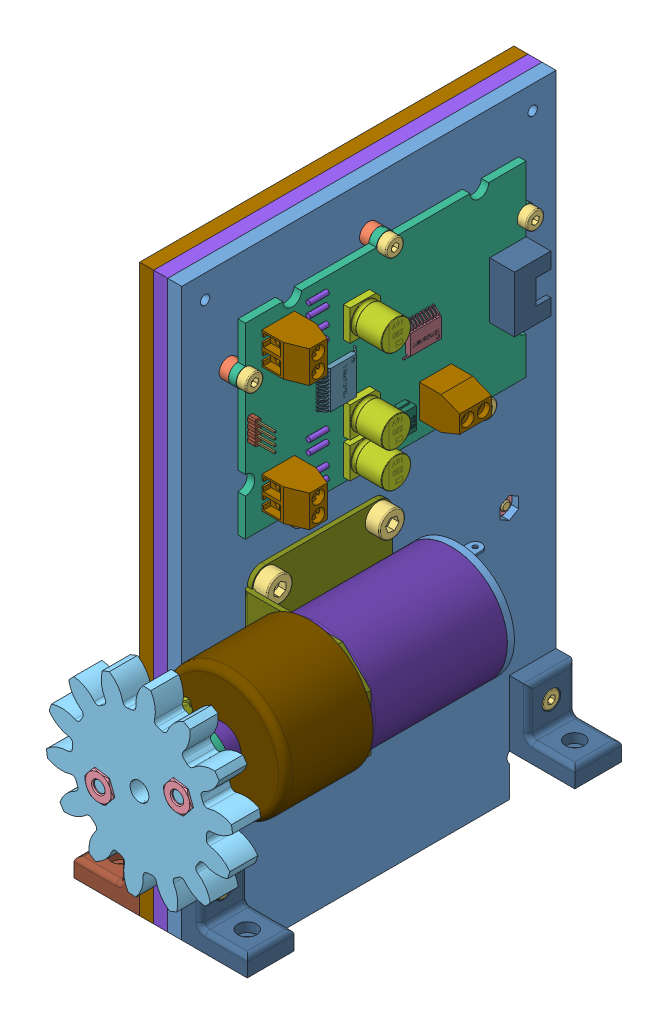
SolidWorks assembly moteur-complet, configuration Défaut. Lengths in mm.
Overall size (62.95 130 103.93).
88 component instances, 29 part files, 109 mates.
Components (placement in the parent):
- moteur-platine-1-4: moteur-platine-1 [Défaut] at (-59.9962 -68.9698 170) size (3 130 80)
- Grove button-1: Grove button [Défaut] at (-66.7015 -12.8903 110) x (0 -1 0) z (0 0 -1) size (20 11.6 23.6)
  - PCB grove 20x20-1: PCB grove 20x20 [Défaut] at (2.0795 1.2947 0) size (20 1.6 23.6)
  - 603 resistor 102-1: 603 resistor 102 [Default] at (2.0895 2.8947 -6.319) x (0 0 1) z (-1 0 0) size (2.36 0.62 1.03)
  - tactileswitch-CMS-1: tactileswitch-CMS [Default] at (-2.4169 2.8947 0.0035) x (0 0 1) z (-1 0 0) size (8.41 4.95 6.01)
  - Connecteur Grove (droit CMS)-1: Connecteur Grove (droit CMS) [Défaut] at (5.0795 2.8947 0) x (-1 0 0) z (0 1 0) size (6.5 14 10)
  - 603 resistor 102-2: 603 resistor 102 [Default] at (3.5895 2.8947 -6.319) x (0 0 1) z (-1 0 0) size (2.36 0.62 1.03)
- Grove I2C Motor driver TB6612FNG-1: Grove I2C Motor driver TB6612FNG [Défaut] at (-118.1962 28.5169 135.6463) x (0 0 1) z (1 0 0) size (64 44 12.2)
  - Plaque de base-1: Plaque de base [Défaut] at (-5.6463 -2.5133 63.2) size (64 44 1.6)
  - CS 220 16V-1: CS 220 16V [Défaut] at (0.1237 13.2167 64.8) x (1 0 0) z (0 -1 0) size (6.54 8.01 6.54)
  - CS 220 16V-2: CS 220 16V [Défaut] at (0.1237 5.6767 64.8) x (1 0 0) z (0 -1 0) size (6.54 8.01 6.54)
  - CS 220 16V-3: CS 220 16V [Défaut] at (0.1237 -12.2433 64.8) x (1 0 0) z (0 -1 0) size (6.54 8.01 6.54)
  - D1-1: D1 [Défaut] at (7.4081 5.2819 65.3) x (0 0.946795 -0.321836) z (1 0 0) size (1 1 4)
  - D1-2: D1 [Défaut] at (7.4081 7.7235 65.3) x (0 0.786026 0.618193) z (1 0 0) size (1 1 4)
  - D1-3: D1 [Défaut] at (7.4081 14.4025 65.3) x (0 0.953842 0.300308) z (1 0 0) size (1 1 4)
  - D1-4: D1 [Défaut] at (7.4081 11.9602 65.3) x (0 0.659384 0.751806) z (1 0 0) size (1 1 4)
  - D1-5: D1 [Défaut] at (7.4081 -17.5815 65.3) x (0 -0.999835 -0.018161) z (1 0 0) size (1 1 4)
  - D1-6: D1 [Défaut] at (7.4081 -14.133 65.3) x (0 0.806812 -0.590809) z (1 0 0) size (1 1 4)
  - D1-7: D1 [Défaut] at (7.4081 -11.4343 65.3) x (0 -0.166774 0.985995) z (1 0 0) size (1 1 4)
  - D1-8: D1 [Défaut] at (7.4081 -20.0356 65.3) x (0 0.962631 -0.270816) z (1 0 0) size (1 1 4)
  - bornier double-1: bornier double [Défaut] at (20.8537 7.1995 64.8) x (0 1 0) z (1 0 0) size (6.8 12.2 7)
  - bornier double-2: bornier double [Défaut] at (-12.8463 13.9867 64.8) x (-1 0 0) z (0 1 0) size (6.8 12.2 7)
  - bornier double-3: bornier double [Défaut] at (20.8537 -19.5133 64.8) x (0 1 0) z (1 0 0) size (6.8 12.2 7)
  - Grove Connecteur-1: Grove Connecteur [Défaut] at (-37.0963 -2.5133 64.05) x (1 0 0) z (0 -1 0) size (7.8 5.3 12)
  - Bloc 4 pins male-1: Bloc 4 pins male [Défaut] at (23.2493 -0.7812 63.276) x (0 -1 0) z (0 0 1) size (5.08 1.27 7.62)
    - Pin_cmi2c_Base-1: Pin_cmi2c_Base [Défaut] at (-0.1729 -0.0306 1.524) size (1.27 1.27 1.52)
    - Pin_cmi2c-1: Pin_cmi2c [Défaut] at (-0.1729 0.1472 -0.762) x (1 0 0) z (0 -1 0) size (0.36 7.62 0.36)
    - Pin_cmi2c-2: Pin_cmi2c [Défaut] at (1.0971 0.1472 -0.762) x (1 0 0) z (0 -1 0) size (0.36 7.62 0.36)
    - Pin_cmi2c-3: Pin_cmi2c [Défaut] at (2.3671 0.1472 -0.762) x (1 0 0) z (0 -1 0) size (0.36 7.62 0.36)
    - Pin_cmi2c-4: Pin_cmi2c [Défaut] at (3.6371 0.1472 -0.762) x (1 0 0) z (0 -1 0) size (0.36 7.62 0.36)
    - Pin_cmi2c_Base-2: Pin_cmi2c_Base [Défaut] at (1.0971 -0.0306 1.524) size (1.27 1.27 1.52)
    - Pin_cmi2c_Base-3: Pin_cmi2c_Base [Défaut] at (2.3671 -0.0306 1.524) size (1.27 1.27 1.52)
    - Pin_cmi2c_Base-4: Pin_cmi2c_Base [Défaut] at (3.6371 -0.0306 1.524) size (1.27 1.27 1.52)
  - Microcontroller 32F030F4P6-1: Microcontroller 32F030F4P6 [Défaut] at (-12.4961 -2.5519 65.5199) size (6.61 6.93 1.72)
  - Microcontroller TB6612FNG-1: Microcontroller TB6612FNG [Défaut] at (5.1421 -2.7086 65.5199) x (0 1 0) z (0 0 1) size (8 8.26 1.72)
  - PK13-1: PK13 [Défaut] at (-8.5328 11.2953 64.8) x (0 -1 0) z (-1 0 0) size (5.33 2 3.32)
- moteur MFA-1: moteur MFA [Défaut] at (-44.4916 -13.5198 141.6132) x (0 0 -1) z (0 -1 0) size (69.13 27.9 30)
  - moteur-support-1: moteur-support [Défaut] at (-14.3868 -12.5047 0) size (31 26.4 30)
  - moteur-corps-1: moteur-corps [Défaut] at (14.8132 1.8953 0) x (0 0 1) z (-1 0 0) size (24 24 62.63)
  - moteur-capuchon-1: moteur-capuchon [Défaut] at (-15.3868 1.8953 0) x (0 0 1) z (-1 0 0) size (27 27 18.7)
  - moteur-arriere-1: moteur-arriere [Défaut] at (16.3132 1.8953 0) x (0 0 1) z (-1 0 0) size (24 24 6.5)
- entretoise-grove-1: entretoise-grove [Défaut] at (-54.9962 51.0302 130) x (0 0.271539 0.962428) z (-1 0 0) size (4 4 2)
- entretoise-grove-2: entretoise-grove [Défaut] at (-54.9962 41.0302 100) x (0 0.358036 0.933708) z (-1 0 0) size (4 4 2)
- entretoise-grove-3: entretoise-grove [Défaut] at (-54.9962 41.0302 160) x (0 -0.42455 0.905404) z (-1 0 0) size (4 4 2)
- entretoise-grove-4: entretoise-grove [Défaut] at (-54.9962 11.0302 150) x (0 0 1) z (-1 0 0) size (4 4 2)
- entretoise-grove-5: entretoise-grove [Défaut] at (-54.9962 11.0302 110) x (0 0.014886 0.999889) z (-1 0 0) size (4 4 2)
- entretoise-grove-6: entretoise-grove [Défaut] at (-67.9962 -14.9698 120) x (0 0.014606 -0.999893) z (1 0 0) size (4 4 2)
- entretoise-grove-7: entretoise-grove [Défaut] at (-67.9962 -14.9698 100) x (0 0.432952 0.901417) z (1 0 0) size (4 4 2)
- vis-chc-1: vis-chc [Vis CHC M2x12] at (-69.5962 -14.9698 100) x (0 0.697993 -0.716105) z (0 0.716105 0.697993) size (3.8 14 3.8)
- vis-chc-2: vis-chc [Vis CHC M2x12] at (-69.5962 -14.9698 120) x (0 0.185382 -0.982666) z (0 0.982666 0.185382) size (3.8 14 3.8)
- vis-chc-3: vis-chc [Vis CHC M2x12] at (-53.3962 41.0302 100) x (0 0.381849 -0.924225) z (0 -0.924225 -0.381849) size (3.8 14 3.8)
- vis-chc-4: vis-chc [Vis CHC M2x12] at (-53.3962 51.0302 130) x (0 0.381849 -0.924225) z (0 -0.924225 -0.381849) size (3.8 14 3.8)
- vis-chc-5: vis-chc [Vis CHC M2x12] at (-53.3962 41.0302 160) x (0 0.381849 -0.924225) z (0 -0.924225 -0.381849) size (3.8 14 3.8)
- vis-chc-6: vis-chc [Vis CHC M2x12] at (-53.3962 11.0302 150) x (0 0.381849 -0.924225) z (0 -0.924225 -0.381849) size (3.8 14 3.8)
- vis-chc-7: vis-chc [Vis CHC M2x12] at (-53.3962 11.0302 110) x (0 0.381849 -0.924225) z (0 -0.924225 -0.381849) size (3.8 14 3.8)
- ecrou-h-2: ecrou-h [6007 HU M2] at (-59.9962 -14.9698 120) x (0 0.866025 0.5) z (0 -0.5 0.866025) size (4 1.6 4.62)
- ecrou-h-3: ecrou-h [6007 HU M2] at (-59.9962 -14.9698 100) x (0 0 1) z (0 -1 0) size (4 1.6 4.62)
- ecrou-h-4: ecrou-h [6007 HU M2] at (-64.5962 11.0302 110) x (0 0.866025 0.5) z (0 -0.5 0.866025) size (4 1.6 4.62)
- ecrou-h-5: ecrou-h [6007 HU M2] at (-64.5962 11.0302 150) x (0 0.866025 0.5) z (0 -0.5 0.866025) size (4 1.6 4.62)
- ecrou-h-6: ecrou-h [6007 HU M2] at (-64.5962 41.0302 160) x (0 0.866025 0.5) z (0 -0.5 0.866025) size (4 1.6 4.62)
- ecrou-h-7: ecrou-h [6007 HU M2] at (-64.5962 51.0302 130) x (0 0.866025 0.5) z (0 -0.5 0.866025) size (4 1.6 4.62)
- ecrou-h-8: ecrou-h [6007 HU M2] at (-64.5962 41.0302 100) x (0 0.866025 0.5) z (0 -0.5 0.866025) size (4 1.6 4.62)
- vis-chc-8: vis-chc [Vis CHC M3x10] at (-55.9962 -1.5198 129) x (0 0.773717 -0.633531) z (0 -0.633531 -0.773717) size (5.5 13 5.5)
- vis-chc-9: vis-chc [Vis CHC M3x10] at (-55.9962 -1.5198 153) x (0 0.483049 -0.875594) z (0 -0.875594 -0.483049) size (5.5 13 5.5)
- vis-chc-10: vis-chc [Vis CHC M3x10] at (-55.9962 -25.5198 153) x (0 0.381849 -0.924225) z (0 -0.924225 -0.381849) size (5.5 13 5.5)
- vis-chc-11: vis-chc [Vis CHC M3x10] at (-55.9962 -25.5198 129) x (0 0.381849 -0.924225) z (0 -0.924225 -0.381849) size (5.5 13 5.5)
- ecrou-h-9: ecrou-h [6012 HU M3] at (-65.3962 -1.5198 153) x (0 0.866025 0.5) z (0 -0.5 0.866025) size (5.5 2.4 6.35)
- ecrou-h-10: ecrou-h [6012 HU M3] at (-65.3962 -25.5198 153) x (0 0.866025 0.5) z (0 -0.5 0.866025) size (5.5 2.4 6.35)
- ecrou-h-11: ecrou-h [6012 HU M3] at (-65.3962 -25.5198 129) x (0 0.866025 -0.5) z (0 0.5 0.866025) size (5.5 2.4 6.35)
- ecrou-h-12: ecrou-h [6012 HU M3] at (-65.3962 -1.5198 129) x (0 0.866025 -0.5) z (0 0.5 0.866025) size (5.5 2.4 6.35)
- vis-chc-14: vis-chc [Vis CHC M2x16] at (-54.9962 -50.9698 95) x (0 -0.431797 -0.901971) z (0 -0.901971 0.431797) size (3.8 18 3.8)
- vis-chc-15: vis-chc [Vis CHC M2x16] at (-54.9962 -50.9698 165) x (0 0.381849 -0.924225) z (0 -0.924225 -0.381849) size (3.8 18 3.8)
- ecrou-h-15: ecrou-h [6007 HU M2] at (-69.5962 -50.9698 165) x (0 1 0) z (0 0 1) size (4 1.6 4.62)
- ecrou-h-16: ecrou-h [6007 HU M2] at (-69.5962 -50.9698 95) x (0 0.5 0.866025) z (0 -0.866025 0.5) size (4 1.6 4.62)
- engrenage-complet-1: engrenage-complet [Défaut] at (-42.1676 -13.7474 193.43) x (0.932852 0.36026 0) z (0 0 -1) size (39.32 40 14.86)
  - engrenage-1: engrenage [Défaut] at (1.0609 0.1936 0) size (39.32 40 6)
  - engrenage-bague_arret-1: engrenage-bague_arret [Défaut] at (-0.3178 -0.3667 13.5) x (-1 0 0) z (0 0 -1) size (24 24 8)
  - vis-tc-m3x6-1: vis-tc-m3x6 [Défaut] at (-0.3178 -8.4167 10.5) x (-0.611546 0 0.791209) z (0.791209 0 0.611546) size (5.5 7.83 5.5)
  - vis-chc-1: vis-chc [Vis CHC M3x8] at (-9.3178 -0.3667 7.5) x (0.40091 -0.916118 0) z (-0.916118 -0.40091 0) size (5.5 11 5.5)
  - vis-chc-2: vis-chc [Vis CHC M3x8] at (8.6822 -0.3667 7.5) x (0.998484 0.055044 0) z (0.055044 -0.998484 0) size (5.5 11 5.5)
  - ecrou-h-1: ecrou-h [6012 HU M3] at (8.6822 -0.3667 -0.4) x (1 0 0) z (0 1 0) size (5.5 2.4 6.35)
  - ecrou-h-2: ecrou-h [6012 HU M3] at (-9.3178 -0.3667 -0.4) x (1 0 0) z (0 1 0) size (5.5 2.4 6.35)
- moteur-platine-2-5: moteur-platine-2 [Défaut] at (-62.9962 -68.9698 170) size (3 130 80)
- moteur-platine-3-3: moteur-platine-3 [Défaut] at (-65.9962 -68.9698 170) size (3 130 80)
- equerre-3: equerre [Défaut] at (-56.9962 -59.9698 165) x (0 0 -1) z (1 0 0) size (10 14 14)
- equerre-2: equerre [Défaut] at (-56.9962 -59.9698 95) x (0 0 -1) z (1 0 0) size (10 14 14)
- equerre-ecrou-1: equerre-ecrou [Défaut] at (-65.9962 -59.9698 95) x (0 0 1) z (-1 0 0) size (10 14 14)
- equerre-ecrou-2: equerre-ecrou [Défaut] at (-65.9962 -59.9698 165) x (0 0 1) z (-1 0 0) size (10 14 14)
Mates (geometry in assembly coordinates):
- Coïncidente1: coincident anti-aligned: plane of moteur-platine-1-4 through (-56.9962 -61.1012 161.1314) normal (1 0 0); plane of moteur MFA-1/moteur-support-1 through (-56.9962 -25.5198 153) normal (-1 0 0)
- Coaxiale1: concentric anti-aligned: cylinder of moteur-platine-1-4 through (-59.9962 -1.5198 129) axis (1 0 0) radius 1.5; cylinder of moteur MFA-1/moteur-support-1 through (-30.5962 -1.5198 129) axis (-1 0 0) radius 1.65
- Coaxiale2: concentric anti-aligned: cylinder of moteur-platine-1-4 through (-59.9962 -25.5198 129) axis (1 0 0) radius 1.5; cylinder of moteur MFA-1/moteur-support-1 through (-30.5962 -25.5198 129) axis (-1 0 0) radius 1.65
- Parallèle1: parallel aligned: plane of moteur-platine-1-4 through (-56.9962 61.0302 90) normal (0 0 -1); plane of Grove I2C Motor driver TB6612FNG-1/Plaque de base-1 through (-53.3962 11.0302 100) normal (0 0 -1)
- Parallèle2: parallel aligned: plane of moteur-platine-1-4 through (-56.9962 61.0302 170) normal (0 1 0); plane of Grove I2C Motor driver TB6612FNG-1/Plaque de base-1 through (-53.3962 51.0302 132) normal (0 1 0)
- Coaxiale3: concentric anti-aligned: cylinder of Grove I2C Motor driver TB6612FNG-1/Plaque de base-1 through (-53.3962 11.0302 110) axis (-1 0 0) radius 1; cylinder of entretoise-grove-5 through (-56.9962 11.0302 110) axis (1 0 0) radius 1
- Coïncidente4: coincident anti-aligned: plane of Grove I2C Motor driver TB6612FNG-1/Plaque de base-1 through (-54.9962 21.0302 100) normal (-1 0 0); plane of entretoise-grove-5 through (-54.9962 11.0302 110) normal (1 0 0)
- Coaxiale4: concentric anti-aligned: cylinder of Grove I2C Motor driver TB6612FNG-1/Plaque de base-1 through (-53.3962 11.0302 150) axis (-1 0 0) radius 1; cylinder of entretoise-grove-4 through (-56.9962 11.0302 150) axis (1 0 0) radius 1
- Coïncidente5: coincident anti-aligned: plane of Grove I2C Motor driver TB6612FNG-1/Plaque de base-1 through (-54.9962 21.0302 100) normal (-1 0 0); plane of entretoise-grove-4 through (-54.9962 11.0302 150) normal (1 0 0)
- Coaxiale5: concentric anti-aligned: cylinder of Grove I2C Motor driver TB6612FNG-1/Plaque de base-1 through (-53.3962 41.0302 100) axis (-1 0 0) radius 1; cylinder of entretoise-grove-2 through (-56.9962 41.0302 100) axis (1 0 0) radius 1
- Coïncidente6: coincident anti-aligned: plane of Grove I2C Motor driver TB6612FNG-1/Plaque de base-1 through (-54.9962 21.0302 100) normal (-1 0 0); plane of entretoise-grove-2 through (-54.9962 41.0302 100) normal (1 0 0)
- Coaxiale6: concentric anti-aligned: cylinder of Grove I2C Motor driver TB6612FNG-1/Plaque de base-1 through (-53.3962 41.0302 160) axis (-1 0 0) radius 1; cylinder of entretoise-grove-3 through (-56.9962 41.0302 160) axis (1 0 0) radius 1
- Coïncidente7: coincident anti-aligned: plane of Grove I2C Motor driver TB6612FNG-1/Plaque de base-1 through (-54.9962 21.0302 100) normal (-1 0 0); plane of entretoise-grove-3 through (-54.9962 41.0302 160) normal (1 0 0)
- Coaxiale7: concentric anti-aligned: cylinder of Grove I2C Motor driver TB6612FNG-1/Plaque de base-1 through (-53.3962 51.0302 130) axis (-1 0 0) radius 1; cylinder of entretoise-grove-1 through (-56.9962 51.0302 130) axis (1 0 0) radius 1
- Coïncidente8: coincident anti-aligned: plane of Grove I2C Motor driver TB6612FNG-1/Plaque de base-1 through (-54.9962 21.0302 100) normal (-1 0 0); plane of entretoise-grove-1 through (-54.9962 51.0302 130) normal (1 0 0)
- Coïncidente9: coincident anti-aligned: plane of moteur-platine-1-4 through (-56.9962 -61.1012 161.1314) normal (1 0 0); plane of entretoise-grove-3 through (-56.9962 41.0302 160) normal (-1 0 0)
- Coaxiale8: concentric aligned: cylinder of moteur-platine-1-4 through (-59.9962 11.0302 150) axis (1 0 0) radius 1; cylinder of entretoise-grove-4 through (-56.9962 11.0302 150) axis (1 0 0) radius 1
- Coaxiale9: concentric anti-aligned: cylinder of Grove button-1/PCB grove 20x20-1 through (-69.5962 -14.9698 120) axis (1 0 0) radius 1.1; cylinder of entretoise-grove-6 through (-65.9962 -14.9698 120) axis (-1 0 0) radius 1
- Coaxiale10: concentric anti-aligned: cylinder of Grove button-1/PCB grove 20x20-1 through (-69.5962 -14.9698 100) axis (1 0 0) radius 1.1; cylinder of entretoise-grove-7 through (-65.9962 -14.9698 100) axis (-1 0 0) radius 1
- Coïncidente11: coincident anti-aligned: plane of Grove button-1/PCB grove 20x20-1 through (-67.9962 -14.9698 110) normal (1 0 0); plane of entretoise-grove-7 through (-67.9962 -14.9698 100) normal (-1 0 0)
- Coaxiale13: concentric anti-aligned: cylinder of moteur MFA-1/moteur-corps-1 through (-42.5962 -13.5198 189.43) axis (0 0 -1) radius 2; cylinder of engrenage-complet-1/engrenage-bague_arret-1 through (-42.5962 -13.5198 179.93) axis (0 0 1) radius 2.05
- Distance1: distance = 0.5 mm anti-aligned: plane of engrenage-complet-1/engrenage-bague_arret-1 through (-42.5962 -13.5198 179.93) normal (0 0 -1); plane of moteur MFA-1/moteur-corps-1 through (-42.5962 -13.5198 179.43) normal (0 0 1)
- Coïncidente12: coincident anti-aligned: plane of moteur-platine-1-4 through (-59.9962 -61.1012 161.1314) normal (-1 0 0); plane of moteur-platine-2-5 through (-59.9962 -61.1012 161.1314) normal (1 0 0)
- Coïncidente13: coincident aligned: plane of moteur-platine-1-4 through (-56.9962 61.0302 170) normal (0 1 0); plane of moteur-platine-2-5 through (-59.9962 61.0302 170) normal (0 1 0)
- Coïncidente14: coincident aligned: plane of moteur-platine-1-4 through (-56.9962 61.0302 90) normal (0 0 -1); plane of moteur-platine-2-5 through (-59.9962 61.0302 90) normal (0 0 -1)
- Coïncidente15: coincident anti-aligned: plane of moteur-platine-2-5 through (-62.9962 -61.1012 161.1314) normal (-1 0 0); plane of moteur-platine-3-3 through (-62.9962 -61.1012 161.1314) normal (1 0 0)
- Coïncidente16: coincident aligned: plane of moteur-platine-2-5 through (-59.9962 61.0302 170) normal (0 1 0); plane of moteur-platine-3-3 through (-62.9962 61.0302 170) normal (0 1 0)
- Coïncidente17: coincident aligned: plane of moteur-platine-1-4 through (-56.9962 61.0302 90) normal (0 0 -1); plane of moteur-platine-3-3 through (-62.9962 61.0302 90) normal (0 0 -1)
- Coïncidente18: coincident anti-aligned: plane of entretoise-grove-7 through (-65.9962 -14.9698 100) normal (1 0 0); plane of moteur-platine-3-3 through (-65.9962 -61.1012 161.1314) normal (-1 0 0)
- Coïncidente19: coincident anti-aligned: plane of entretoise-grove-6 through (-65.9962 -14.9698 120) normal (1 0 0); plane of moteur-platine-3-3 through (-65.9962 -61.1012 161.1314) normal (-1 0 0)
- Coïncidente21: coincident anti-aligned: plane of Grove button-1/PCB grove 20x20-1 through (-69.5962 -14.9698 110) normal (-1 0 0); plane of vis-chc-2 through (-69.5962 -14.9698 120) normal (1 0 0)
- Coaxiale15: concentric aligned: cylinder of vis-chc-2 through (-57.5962 -14.9698 120) axis (-1 0 0) radius 1; cylinder of ecrou-h-2 through (-58.3962 -14.9698 120) axis (-1 0 0) radius 0.7835
- Parallèle4: parallel aligned: plane of moteur-platine-1-4 through (-56.9962 61.0302 90) normal (0 0 -1); plane of ecrou-h-2 through (-58.3962 -13.8151 118) normal (0 0 -1)
- Coïncidente25: coincident anti-aligned: plane of Grove button-1/PCB grove 20x20-1 through (-69.5962 -14.9698 110) normal (-1 0 0); plane of vis-chc-1 through (-69.5962 -14.9698 100) normal (1 0 0)
- Coaxiale17: concentric aligned: cylinder of vis-chc-1 through (-57.5962 -14.9698 100) axis (-1 0 0) radius 1; cylinder of ecrou-h-3 through (-58.3962 -14.9698 100) axis (-1 0 0) radius 0.7835
- Parallèle5: parallel aligned: plane of moteur-platine-1-4 through (-56.9962 61.0302 90) normal (0 0 -1); plane of ecrou-h-3 through (-58.3962 -13.8151 98) normal (0 0 -1)
- Coaxiale18: concentric anti-aligned: cylinder of Grove I2C Motor driver TB6612FNG-1/Plaque de base-1 through (-53.3962 11.0302 110) axis (-1 0 0) radius 1; cylinder of vis-chc-7 through (-65.3962 11.0302 110) axis (1 0 0) radius 1
- Coaxiale19: concentric anti-aligned: cylinder of Grove I2C Motor driver TB6612FNG-1/Plaque de base-1 through (-53.3962 11.0302 150) axis (-1 0 0) radius 1; cylinder of vis-chc-6 through (-65.3962 11.0302 150) axis (1 0 0) radius 1
- Coaxiale20: concentric anti-aligned: cylinder of Grove I2C Motor driver TB6612FNG-1/Plaque de base-1 through (-53.3962 41.0302 160) axis (-1 0 0) radius 1; cylinder of vis-chc-5 through (-65.3962 41.0302 160) axis (1 0 0) radius 1
- Coaxiale21: concentric anti-aligned: cylinder of Grove I2C Motor driver TB6612FNG-1/Plaque de base-1 through (-53.3962 51.0302 130) axis (-1 0 0) radius 1; cylinder of vis-chc-4 through (-65.3962 51.0302 130) axis (1 0 0) radius 1
- Coaxiale22: concentric anti-aligned: cylinder of Grove I2C Motor driver TB6612FNG-1/Plaque de base-1 through (-53.3962 41.0302 100) axis (-1 0 0) radius 1; cylinder of vis-chc-3 through (-65.3962 41.0302 100) axis (1 0 0) radius 1
- Coïncidente28: coincident anti-aligned: plane of Grove I2C Motor driver TB6612FNG-1/Plaque de base-1 through (-53.3962 21.0302 100) normal (1 0 0); plane of vis-chc-3 through (-53.3962 41.0302 100) normal (-1 0 0)
- Coïncidente29: coincident anti-aligned: plane of Grove I2C Motor driver TB6612FNG-1/Plaque de base-1 through (-53.3962 21.0302 100) normal (1 0 0); plane of vis-chc-4 through (-53.3962 51.0302 130) normal (-1 0 0)
- Coïncidente30: coincident anti-aligned: plane of Grove I2C Motor driver TB6612FNG-1/Plaque de base-1 through (-53.3962 21.0302 100) normal (1 0 0); plane of vis-chc-5 through (-53.3962 41.0302 160) normal (-1 0 0)
- Coïncidente31: coincident anti-aligned: plane of Grove I2C Motor driver TB6612FNG-1/Plaque de base-1 through (-53.3962 21.0302 100) normal (1 0 0); plane of vis-chc-6 through (-53.3962 11.0302 150) normal (-1 0 0)
- Coïncidente32: coincident anti-aligned: plane of Grove I2C Motor driver TB6612FNG-1/Plaque de base-1 through (-53.3962 21.0302 100) normal (1 0 0); plane of vis-chc-7 through (-53.3962 11.0302 110) normal (-1 0 0)
- Coaxiale23: concentric anti-aligned: cylinder of vis-chc-7 through (-65.3962 11.0302 110) axis (1 0 0) radius 1; cylinder of ecrou-h-4 through (-62.9962 11.0302 110) axis (-1 0 0) radius 0.7835
- Coaxiale24: concentric anti-aligned: cylinder of vis-chc-3 through (-65.3962 41.0302 100) axis (1 0 0) radius 1; cylinder of ecrou-h-8 through (-62.9962 41.0302 100) axis (-1 0 0) radius 0.7835
- Coaxiale25: concentric anti-aligned: cylinder of vis-chc-4 through (-65.3962 51.0302 130) axis (1 0 0) radius 1; cylinder of ecrou-h-7 through (-62.9962 51.0302 130) axis (-1 0 0) radius 0.7835
- Coaxiale26: concentric anti-aligned: cylinder of vis-chc-5 through (-65.3962 41.0302 160) axis (1 0 0) radius 1; cylinder of ecrou-h-6 through (-62.9962 41.0302 160) axis (-1 0 0) radius 0.7835
- Coaxiale27: concentric anti-aligned: cylinder of vis-chc-6 through (-65.3962 11.0302 150) axis (1 0 0) radius 1; cylinder of ecrou-h-5 through (-62.9962 11.0302 150) axis (-1 0 0) radius 0.7835
- Parallèle6: parallel aligned: plane of moteur-platine-3-3 through (-62.9962 -59.9698 170) normal (0 0 1); plane of ecrou-h-6 through (-62.9962 39.8755 162) normal (0 0 1)
- Parallèle7: parallel aligned: plane of moteur-platine-3-3 through (-62.9962 -59.9698 170) normal (0 0 1); plane of ecrou-h-7 through (-62.9962 49.8755 132) normal (0 0 1)
- Parallèle8: parallel aligned: plane of moteur-platine-3-3 through (-62.9962 -59.9698 170) normal (0 0 1); plane of ecrou-h-8 through (-62.9962 39.8755 102) normal (0 0 1)
- Parallèle9: parallel aligned: plane of moteur-platine-3-3 through (-62.9962 -59.9698 170) normal (0 0 1); plane of ecrou-h-5 through (-62.9962 9.8755 152) normal (0 0 1)
- Parallèle10: parallel aligned: plane of moteur-platine-3-3 through (-62.9962 -59.9698 170) normal (0 0 1); plane of ecrou-h-4 through (-62.9962 9.8755 112) normal (0 0 1)
- Coaxiale28: concentric anti-aligned: cylinder of moteur MFA-1/moteur-support-1 through (-30.5962 -1.5198 153) axis (-1 0 0) radius 1.65; cylinder of vis-chc-9 through (-65.9962 -1.5198 153) axis (1 0 0) radius 1.5
- Coaxiale29: concentric anti-aligned: cylinder of moteur MFA-1/moteur-support-1 through (-30.5962 -1.5198 129) axis (-1 0 0) radius 1.65; cylinder of vis-chc-8 through (-65.9962 -1.5198 129) axis (1 0 0) radius 1.5
- Coaxiale30: concentric anti-aligned: cylinder of moteur MFA-1/moteur-support-1 through (-30.5962 -25.5198 129) axis (-1 0 0) radius 1.65; cylinder of vis-chc-11 through (-65.9962 -25.5198 129) axis (1 0 0) radius 1.5
- Coaxiale31: concentric anti-aligned: cylinder of moteur MFA-1/moteur-support-1 through (-30.5962 -25.5198 153) axis (-1 0 0) radius 1.65; cylinder of vis-chc-10 through (-65.9962 -25.5198 153) axis (1 0 0) radius 1.5
- Coïncidente43: coincident anti-aligned: plane of moteur MFA-1/moteur-support-1 through (-55.9962 -29.752 156) normal (1 0 0); plane of vis-chc-11 through (-55.9962 -25.5198 129) normal (-1 0 0)
- Coïncidente44: coincident aligned: plane of moteur MFA-1/moteur-support-1 through (-55.9962 -29.752 156) normal (1 0 0); circle of vis-chc-10
- Coïncidente45: coincident anti-aligned: plane of moteur MFA-1/moteur-support-1 through (-55.9962 -29.752 156) normal (1 0 0); plane of vis-chc-8 through (-55.9962 -1.5198 129) normal (-1 0 0)
- Coïncidente46: coincident anti-aligned: plane of moteur MFA-1/moteur-support-1 through (-55.9962 -29.752 156) normal (1 0 0); plane of vis-chc-9 through (-55.9962 -1.5198 153) normal (-1 0 0)
- Coaxiale32: concentric anti-aligned: cylinder of vis-chc-8 through (-65.9962 -1.5198 129) axis (1 0 0) radius 1.5; cylinder of ecrou-h-12 through (-62.9962 -1.5198 129) axis (-1 0 0) radius 1.2295
- Coaxiale33: concentric anti-aligned: cylinder of vis-chc-10 through (-65.9962 -25.5198 153) axis (1 0 0) radius 1.5; cylinder of ecrou-h-10 through (-62.9962 -25.5198 153) axis (-1 0 0) radius 1.2295
- Coaxiale34: concentric anti-aligned: cylinder of vis-chc-9 through (-65.9962 -1.5198 153) axis (1 0 0) radius 1.5; cylinder of ecrou-h-9 through (-62.9962 -1.5198 153) axis (-1 0 0) radius 1.2295
- Coaxiale35: concentric anti-aligned: cylinder of vis-chc-11 through (-65.9962 -25.5198 129) axis (1 0 0) radius 1.5; cylinder of ecrou-h-11 through (-62.9962 -25.5198 129) axis (-1 0 0) radius 1.2295
- Parallèle11: parallel aligned: plane of moteur-platine-3-3 through (-62.9962 -59.9698 170) normal (0 0 1); plane of ecrou-h-10 through (-62.9962 -27.1075 155.75) normal (0 0 1)
- Parallèle12: parallel aligned: plane of moteur-platine-3-3 through (-62.9962 -59.9698 170) normal (0 0 1); plane of ecrou-h-11 through (-62.9962 -27.1075 131.75) normal (0 0 1)
- Parallèle13: parallel aligned: plane of moteur-platine-3-3 through (-62.9962 -59.9698 170) normal (0 0 1); plane of ecrou-h-12 through (-62.9962 -3.1075 131.75) normal (0 0 1)
- Parallèle14: parallel aligned: plane of moteur-platine-3-3 through (-62.9962 -59.9698 170) normal (0 0 1); plane of ecrou-h-9 through (-62.9962 -3.1075 155.75) normal (0 0 1)
- Coïncidente62: coincident anti-aligned: plane of moteur-platine-1-4 through (-56.9962 -61.1012 161.1314) normal (1 0 0); plane of equerre-2 through (-56.9962 -59.9698 95) normal (-1 0 0)
- Coaxiale41: concentric aligned: cylinder of moteur-platine-1-4 through (-59.9962 -50.9698 95) axis (1 0 0) radius 1; cylinder of equerre-2 through (-56.9962 -50.9698 95) axis (1 0 0) radius 1
- Coïncidente63: coincident aligned: plane of moteur-platine-1-4 through (-56.9962 -59.9698 97.7373) normal (0 -1 0); plane of equerre-2 through (-52.9962 -59.9698 100) normal (0 -1 0)
- Coaxiale42: concentric aligned: cylinder of moteur-platine-1-4 through (-59.9962 -50.9698 165) axis (1 0 0) radius 1; cylinder of equerre-3 through (-56.9962 -50.9698 165) axis (1 0 0) radius 1
- Coïncidente64: coincident aligned: plane of moteur-platine-1-4 through (-56.9962 -59.9698 162.2627) normal (0 -1 0); plane of equerre-3 through (-52.9962 -59.9698 170) normal (0 -1 0)
- Coïncidente65: coincident anti-aligned: plane of moteur-platine-1-4 through (-56.9962 -61.1012 161.1314) normal (1 0 0); plane of equerre-3 through (-56.9962 -59.9698 165) normal (-1 0 0)
- Coaxiale43: concentric aligned: cylinder of vis-chc-15 through (-70.9962 -50.9698 165) axis (1 0 0) radius 1; cylinder of equerre-3 through (-56.9962 -50.9698 165) axis (1 0 0) radius 1
- Coïncidente66: coincident anti-aligned: plane of vis-chc-15 through (-54.9962 -50.9698 165) normal (-1 0 0); plane of equerre-3 through (-54.9962 -50.9698 165) normal (1 0 0)
- Coaxiale44: concentric aligned: cylinder of vis-chc-14 through (-70.9962 -50.9698 95) axis (1 0 0) radius 1; cylinder of equerre-2 through (-56.9962 -50.9698 95) axis (1 0 0) radius 1
- Coïncidente67: coincident anti-aligned: plane of vis-chc-14 through (-54.9962 -50.9698 95) normal (-1 0 0); plane of equerre-2 through (-54.9962 -50.9698 95) normal (1 0 0)
- Coïncidente68: coincident anti-aligned: plane of moteur-platine-3-3 through (-65.9962 -61.1012 161.1314) normal (-1 0 0); plane of equerre-ecrou-2 through (-65.9962 -59.9698 165) normal (1 0 0)
- Coïncidente69: coincident anti-aligned: plane of moteur-platine-3-3 through (-65.9962 -61.1012 161.1314) normal (-1 0 0); plane of equerre-ecrou-1 through (-65.9962 -59.9698 95) normal (1 0 0)
- Coïncidente70: coincident aligned: plane of moteur-platine-3-3 through (-62.9962 -59.9698 97.7373) normal (0 -1 0); plane of equerre-ecrou-1 through (-69.9962 -59.9698 90) normal (0 -1 0)
- Coïncidente71: coincident aligned: plane of moteur-platine-3-3 through (-62.9962 -59.9698 97.7373) normal (0 -1 0); plane of equerre-ecrou-2 through (-69.9962 -59.9698 160) normal (0 -1 0)
- Coaxiale45: concentric anti-aligned: cylinder of vis-chc-14 through (-70.9962 -50.9698 95) axis (1 0 0) radius 1; cylinder of equerre-ecrou-1 through (-65.9962 -50.9698 95) axis (-1 0 0) radius 1
- Coaxiale46: concentric anti-aligned: cylinder of vis-chc-15 through (-70.9962 -50.9698 165) axis (1 0 0) radius 1; cylinder of equerre-ecrou-2 through (-65.9962 -50.9698 165) axis (-1 0 0) radius 1
- Coaxiale47: concentric anti-aligned: cylinder of vis-chc-15 through (-70.9962 -50.9698 165) axis (1 0 0) radius 1; cylinder of ecrou-h-15 through (-67.9962 -50.9698 165) axis (-1 0 0) radius 0.7835
- Parallèle18: parallel anti-aligned: plane of ecrou-h-15 through (-67.9962 -48.9698 166.1547) normal (0 1 0); plane of equerre-ecrou-2 through (-67.9962 -48.952 166.165) normal (0 -1 0)
- Coïncidente73: coincident anti-aligned: plane of ecrou-h-15 through (-67.9962 -48.9698 163.8453) normal (1 0 0); plane of equerre-ecrou-2 through (-67.9962 -59.9698 165) normal (-1 0 0)
- Coaxiale49: concentric anti-aligned: cylinder of vis-chc-14 through (-70.9962 -50.9698 95) axis (1 0 0) radius 1; cylinder of ecrou-h-16 through (-67.9962 -50.9698 95) axis (-1 0 0) radius 0.7835
- Parallèle19: parallel anti-aligned: plane of ecrou-h-16 through (-67.9962 -48.9698 96.1547) normal (0 1 0); plane of equerre-ecrou-1 through (-67.9962 -48.952 96.165) normal (0 -1 0)
- Coïncidente75: coincident anti-aligned: plane of ecrou-h-16 through (-67.9962 -48.9698 96.1547) normal (1 0 0); plane of equerre-ecrou-1 through (-67.9962 -59.9698 95) normal (-1 0 0)
- Coïncidente76: coincident anti-aligned: plane of ecrou-h-6 through (-62.9962 43.3396 160) normal (1 0 0); plane of moteur-platine-2-5 through (-62.9962 -61.1012 161.1314) normal (-1 0 0)
- Coïncidente77: coincident anti-aligned: plane of ecrou-h-5 through (-62.9962 13.3396 150) normal (1 0 0); plane of moteur-platine-2-5 through (-62.9962 -61.1012 161.1314) normal (-1 0 0)
- Coïncidente78: coincident anti-aligned: plane of ecrou-h-4 through (-62.9962 13.3396 110) normal (1 0 0); plane of moteur-platine-2-5 through (-62.9962 -61.1012 161.1314) normal (-1 0 0)
- Coïncidente79: coincident anti-aligned: plane of ecrou-h-8 through (-62.9962 43.3396 100) normal (1 0 0); plane of moteur-platine-2-5 through (-62.9962 -61.1012 161.1314) normal (-1 0 0)
- Coïncidente80: coincident anti-aligned: plane of ecrou-h-7 through (-62.9962 53.3396 130) normal (1 0 0); plane of moteur-platine-2-5 through (-62.9962 -61.1012 161.1314) normal (-1 0 0)
- Coïncidente81: coincident anti-aligned: plane of ecrou-h-12 through (-62.9962 0.0679 126.25) normal (1 0 0); plane of moteur-platine-2-5 through (-62.9962 -61.1012 161.1314) normal (-1 0 0)
- Coïncidente82: coincident anti-aligned: plane of ecrou-h-11 through (-62.9962 -23.9321 126.25) normal (1 0 0); plane of moteur-platine-2-5 through (-62.9962 -61.1012 161.1314) normal (-1 0 0)
- Coïncidente83: coincident anti-aligned: plane of ecrou-h-10 through (-62.9962 -22.3444 153) normal (1 0 0); plane of moteur-platine-2-5 through (-62.9962 -61.1012 161.1314) normal (-1 0 0)
- Coïncidente84: coincident anti-aligned: plane of ecrou-h-9 through (-62.9962 1.6556 153) normal (1 0 0); plane of moteur-platine-2-5 through (-62.9962 -61.1012 161.1314) normal (-1 0 0)
- Coaxiale50: concentric anti-aligned: cylinder of vis-chc-2 through (-57.5962 -14.9698 120) axis (-1 0 0) radius 1; cylinder of moteur-platine-3-3 through (-65.9962 -14.9698 120) axis (1 0 0) radius 1
- Coaxiale51: concentric anti-aligned: cylinder of vis-chc-1 through (-57.5962 -14.9698 100) axis (-1 0 0) radius 1; cylinder of moteur-platine-3-3 through (-65.9962 -14.9698 100) axis (1 0 0) radius 1
- Coïncidente85: coincident anti-aligned: plane of ecrou-h-3 through (-59.9962 -13.8151 102) normal (-1 0 0); plane of moteur-platine-2-5 through (-59.9962 -61.1012 161.1314) normal (1 0 0)
- Coïncidente86: coincident anti-aligned: plane of ecrou-h-2 through (-59.9962 -12.6604 120) normal (-1 0 0); plane of moteur-platine-2-5 through (-59.9962 -61.1012 161.1314) normal (1 0 0)
- Coaxiale52: concentric anti-aligned: cylinder of Grove button-1/PCB grove 20x20-1 through (-69.5962 -14.9698 100) axis (1 0 0) radius 1.1; cylinder of vis-chc-1 through (-57.5962 -14.9698 100) axis (-1 0 0) radius 1
- Coaxiale53: concentric anti-aligned: cylinder of Grove button-1/PCB grove 20x20-1 through (-69.5962 -14.9698 120) axis (1 0 0) radius 1.1; cylinder of vis-chc-2 through (-57.5962 -14.9698 120) axis (-1 0 0) radius 1
